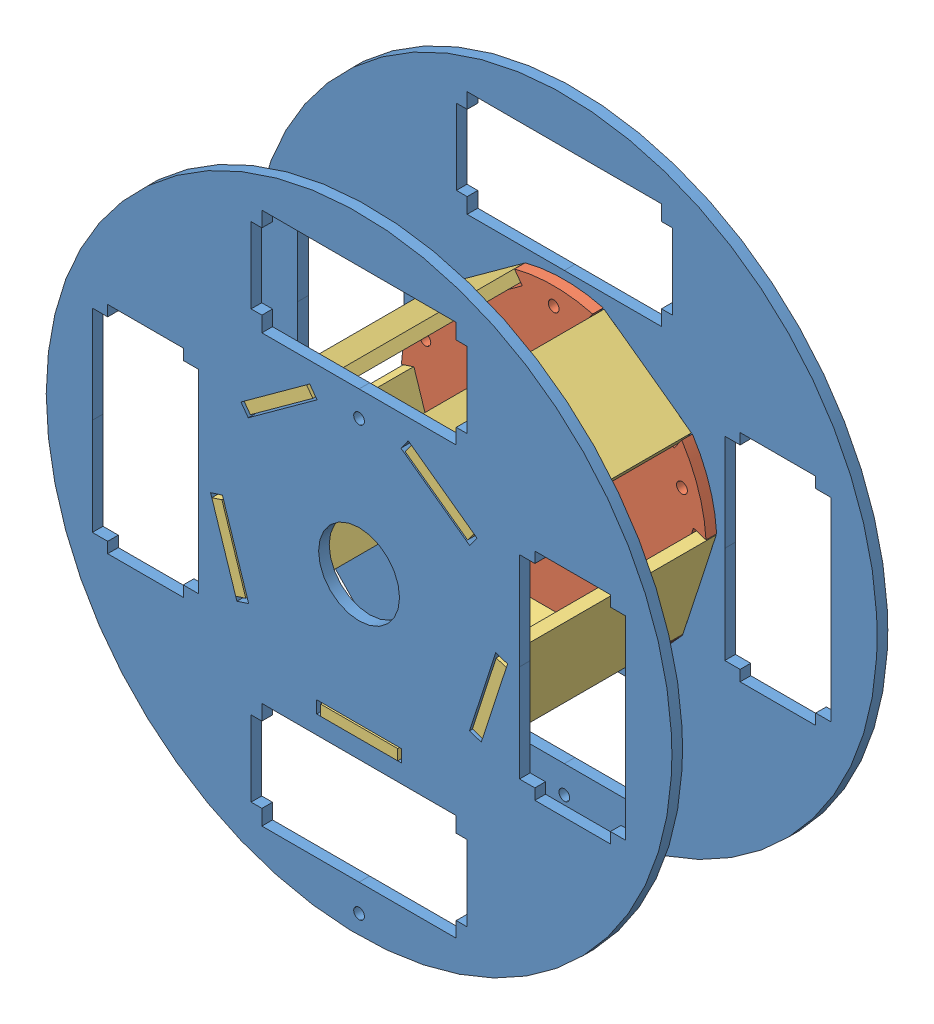
SolidWorks assembly My wooden spool2, configuration Default. Lengths in mm.
Overall size (294.44 294.44 101.6).
8 component instances, 3 part files, 10 mates.
Components (placement in the parent):
- My wooden spool side-1: My wooden spool side [Default] at origin size (294.44 294.44 5)
- My wooden spool glue hub-1: My wooden spool glue hub [Default] at (0 0 5.0038) size (143.36 138.76 5)
- My wooden spool slat-1: My wooden spool slat [Default] at (114.1518 -99.8125 50.8) x (0 0 1) z (-0.587785 0.809017 0) size (101.6 50.8 5)
- My wooden spool slat-2: My wooden spool slat [Default] at (186.9942 -99.7613 50.8) x (0 0 1) z (0.587785 0.809017 0) size (101.6 50.8 5)
- My wooden spool slat-3: My wooden spool slat [Default] at (209.5524 -169.0227 50.8) x (0 0 1) z (0.951057 -0.309017 0) size (101.6 50.8 5)
- My wooden spool slat-4: My wooden spool slat [Default] at (150.6517 -211.8798 50.8) x (0 0 1) z (0 -1 0) size (101.6 50.8 5)
- My wooden spool slat-5: My wooden spool slat [Default] at (91.6909 -169.1055 50.8) x (0 0 1) z (-0.951057 -0.309017 0) size (101.6 50.8 5)
- My wooden spool side-2: My wooden spool side [Default] at (0 0 96.5962) size (294.44 294.44 5)
Mates (geometry in assembly coordinates):
- InPlace1: in place: plane of My wooden spool side-1 through (150.6082 -149.9164 3) normal (0 0 1); plane of ? through (0 0 3) normal (0 0 1); moOrthogonalPlaneRef_w of My wooden spool side-1 through (150.6082 -149.9164 3) normal (0 0 1); plane of ? through (0 0 3) normal (0 1 0); plane of My wooden spool side-1 through (150.6082 -149.9164 3) normal (0 0 1); plane of ? through (0 0 3) normal (1 0 0); plane of My wooden spool side-1 through (150.6082 -149.9164 5.0038) normal (0 0 1); unknown of My wooden spool glue hub-1
- Coincident1: coincident aligned: plane of My wooden spool side-1; plane of My wooden spool glue hub-1
- Coincident2: coincident aligned: moOrthogonalPlaneRef_w of My wooden spool side-1 through (0 0 5.0038) normal (0 1 0); plane of My wooden spool glue hub-1 through (0 0 5.0038) normal (0 1 0)
- Coincident3: coincident anti-aligned: moOrthogonalPlaneRef_w of My wooden spool side-1 through (0 0 5.0038) normal (-1 0 0); plane of My wooden spool glue hub-1 through (0 0 5.0038) normal (1 0 0)
- Coincident4: coincident aligned: plane of My wooden spool side-1 through (150.6082 -149.9164 0) normal (0 0 -1); plane of My wooden spool slat-1 through (125.9032 -85.0895 0) normal (0 0 -1)
- Coincident5: coincident anti-aligned: plane of My wooden spool side-1 through (95.0301 -107.5201 5.0038) normal (0.587785 -0.809017 0); plane of My wooden spool slat-1 through (131.7596 -80.8346 5.08) normal (-0.587785 0.809017 0)
- Width1: width anti-aligned: plane of My wooden spool slat-1 through (96.518 -106.4391 5.08) normal (-0.809017 -0.587785 0); plane of My wooden spool slat-1 through (125.9032 -85.0895 5.08) normal (0.809017 0.587785 0); plane of My wooden spool side-1 through (98.464 -112.2464 5.0038) normal (0.809017 0.587785 0); plane of My wooden spool side-1 through (127.3911 -84.0085 5.0038) normal (-0.809017 -0.587785 0)
- Coincident6: coincident aligned: plane of My wooden spool slat-3 through (208.6992 -187.8411 101.6) normal (0 0 1); plane of My wooden spool side-2 through (150.6082 -149.9164 101.6) normal (0 0 1)
- Concentric1: concentric aligned: cylinder of My wooden spool side-1 through (150.6082 -149.9164 5.0038) axis (0 0 -1) radius 147.2209; cylinder of My wooden spool side-2 through (150.6082 -149.9164 101.6) axis (0 0 -1) radius 147.2209
- Coincident7: coincident aligned: plane of My wooden spool side-1 through (99.8084 -232.644 5.0038) normal (1 -0.000004 0); plane of My wooden spool side-2 through (99.8084 -232.644 101.6) normal (1 -0.000004 0)
